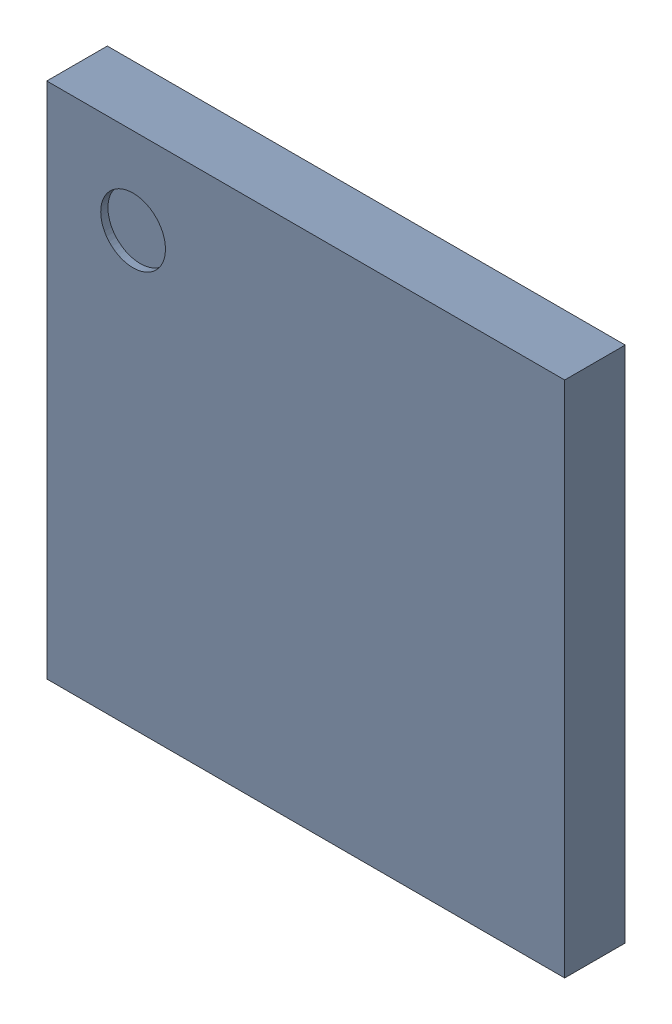
SolidWorks assembly 6297727008.step, configuration Default. Lengths in mm.
Overall size (7.1 9.92 0.85).
187 component instances, 3 part files, 0 mates.
Components (placement in the parent):
- Body (5).step-1: Body (5).step [Default] at (-3.55 -3.55 0.02) size (7.1 7.1 0.83)
  - Open CASCADE STEP translator 6.8 9.2.1.step-1: Open CASCADE STEP translator 6.8 9.2.1.step [Default] at origin size (7.1 7.1 0.83)
- Open CASCADE STEP translator 6.8 9.1.step-1: Open CASCADE STEP translator 6.8 9.1.step [Default] at (-3.55 -3.55 0.02) size (0.9 0.9 0.01)
- pinShape.step-1: pinShape.step [Default] at (-3 -3 0.02) size (0.25 0.25 0.02)
- pinShape.step-2: pinShape.step [Default] at (-2.75 -3 0.02) size (0.25 0.25 0.02)
- pinShape.step-3: pinShape.step [Default] at (-2.5 -3 0.02) size (0.25 0.25 0.02)
- pinShape.step-4: pinShape.step [Default] at (-2.25 -3 0.02) size (0.25 0.25 0.02)
- pinShape.step-5: pinShape.step [Default] at (-2 -3 0.02) size (0.25 0.25 0.02)
- pinShape.step-6: pinShape.step [Default] at (-1.75 -3 0.02) size (0.25 0.25 0.02)
- pinShape.step-7: pinShape.step [Default] at (-1.5 -3 0.02) size (0.25 0.25 0.02)
- pinShape.step-8: pinShape.step [Default] at (-1.25 -3 0.02) size (0.25 0.25 0.02)
- pinShape.step-9: pinShape.step [Default] at (-1 -3 0.02) size (0.25 0.25 0.02)
- pinShape.step-10: pinShape.step [Default] at (-0.75 -3 0.02) size (0.25 0.25 0.02)
- pinShape.step-11: pinShape.step [Default] at (-0.5 -3 0.02) size (0.25 0.25 0.02)
- pinShape.step-12: pinShape.step [Default] at (-0.25 -3 0.02) size (0.25 0.25 0.02)
- pinShape.step-13: pinShape.step [Default] at (0 -3 0.02) size (0.25 0.25 0.02)
- pinShape.step-14: pinShape.step [Default] at (0.25 -3 0.02) size (0.25 0.25 0.02)
- pinShape.step-15: pinShape.step [Default] at (0.5 -3 0.02) size (0.25 0.25 0.02)
- pinShape.step-16: pinShape.step [Default] at (0.75 -3 0.02) size (0.25 0.25 0.02)
- pinShape.step-17: pinShape.step [Default] at (1 -3 0.02) size (0.25 0.25 0.02)
- pinShape.step-18: pinShape.step [Default] at (1.25 -3 0.02) size (0.25 0.25 0.02)
- pinShape.step-19: pinShape.step [Default] at (1.5 -3 0.02) size (0.25 0.25 0.02)
- pinShape.step-20: pinShape.step [Default] at (1.75 -3 0.02) size (0.25 0.25 0.02)
- pinShape.step-21: pinShape.step [Default] at (2 -3 0.02) size (0.25 0.25 0.02)
- pinShape.step-22: pinShape.step [Default] at (2.25 -3 0.02) size (0.25 0.25 0.02)
- pinShape.step-23: pinShape.step [Default] at (2.5 -3 0.02) size (0.25 0.25 0.02)
- pinShape.step-24: pinShape.step [Default] at (2.75 -3 0.02) size (0.25 0.25 0.02)
- pinShape.step-25: pinShape.step [Default] at (3 -3 0.02) size (0.25 0.25 0.02)
- pinShape.step-26: pinShape.step [Default] at (-3 -2.75 0.02) size (0.25 0.25 0.02)
- pinShape.step-27: pinShape.step [Default] at (-2.75 -2.75 0.02) size (0.25 0.25 0.02)
- pinShape.step-28: pinShape.step [Default] at (-2.5 -2.75 0.02) size (0.25 0.25 0.02)
- pinShape.step-29: pinShape.step [Default] at (-2.25 -2.75 0.02) size (0.25 0.25 0.02)
- pinShape.step-30: pinShape.step [Default] at (-2 -2.75 0.02) size (0.25 0.25 0.02)
- pinShape.step-31: pinShape.step [Default] at (-1.75 -2.75 0.02) size (0.25 0.25 0.02)
- pinShape.step-32: pinShape.step [Default] at (-1.5 -2.75 0.02) size (0.25 0.25 0.02)
- pinShape.step-33: pinShape.step [Default] at (-1.25 -2.75 0.02) size (0.25 0.25 0.02)
- pinShape.step-34: pinShape.step [Default] at (-1 -2.75 0.02) size (0.25 0.25 0.02)
- pinShape.step-35: pinShape.step [Default] at (-0.75 -2.75 0.02) size (0.25 0.25 0.02)
- pinShape.step-36: pinShape.step [Default] at (-0.5 -2.75 0.02) size (0.25 0.25 0.02)
- pinShape.step-37: pinShape.step [Default] at (-0.25 -2.75 0.02) size (0.25 0.25 0.02)
- pinShape.step-38: pinShape.step [Default] at (0 -2.75 0.02) size (0.25 0.25 0.02)
- pinShape.step-39: pinShape.step [Default] at (0.25 -2.75 0.02) size (0.25 0.25 0.02)
- pinShape.step-40: pinShape.step [Default] at (0.5 -2.75 0.02) size (0.25 0.25 0.02)
- pinShape.step-41: pinShape.step [Default] at (0.75 -2.75 0.02) size (0.25 0.25 0.02)
- pinShape.step-42: pinShape.step [Default] at (1 -2.75 0.02) size (0.25 0.25 0.02)
- pinShape.step-43: pinShape.step [Default] at (1.25 -2.75 0.02) size (0.25 0.25 0.02)
- pinShape.step-44: pinShape.step [Default] at (1.5 -2.75 0.02) size (0.25 0.25 0.02)
- pinShape.step-45: pinShape.step [Default] at (1.75 -2.75 0.02) size (0.25 0.25 0.02)
- pinShape.step-46: pinShape.step [Default] at (2 -2.75 0.02) size (0.25 0.25 0.02)
- pinShape.step-47: pinShape.step [Default] at (2.25 -2.75 0.02) size (0.25 0.25 0.02)
- pinShape.step-48: pinShape.step [Default] at (2.5 -2.75 0.02) size (0.25 0.25 0.02)
- pinShape.step-49: pinShape.step [Default] at (2.75 -2.75 0.02) size (0.25 0.25 0.02)
- pinShape.step-50: pinShape.step [Default] at (3 -2.75 0.02) size (0.25 0.25 0.02)
- pinShape.step-51: pinShape.step [Default] at (-3 -2.5 0.02) size (0.25 0.25 0.02)
- pinShape.step-52: pinShape.step [Default] at (-2.75 -2.5 0.02) size (0.25 0.25 0.02)
- pinShape.step-53: pinShape.step [Default] at (2.75 -2.5 0.02) size (0.25 0.25 0.02)
- pinShape.step-54: pinShape.step [Default] at (3 -2.5 0.02) size (0.25 0.25 0.02)
- pinShape.step-55: pinShape.step [Default] at (-3 -2.25 0.02) size (0.25 0.25 0.02)
- pinShape.step-56: pinShape.step [Default] at (-2.75 -2.25 0.02) size (0.25 0.25 0.02)
- pinShape.step-57: pinShape.step [Default] at (2.75 -2.25 0.02) size (0.25 0.25 0.02)
- pinShape.step-58: pinShape.step [Default] at (3 -2.25 0.02) size (0.25 0.25 0.02)
- pinShape.step-59: pinShape.step [Default] at (-3 -2 0.02) size (0.25 0.25 0.02)
- pinShape.step-60: pinShape.step [Default] at (-2.75 -2 0.02) size (0.25 0.25 0.02)
- pinShape.step-61: pinShape.step [Default] at (2.75 -2 0.02) size (0.25 0.25 0.02)
- pinShape.step-62: pinShape.step [Default] at (3 -2 0.02) size (0.25 0.25 0.02)
- pinShape.step-63: pinShape.step [Default] at (-3 -1.75 0.02) size (0.25 0.25 0.02)
- pinShape.step-64: pinShape.step [Default] at (-2.75 -1.75 0.02) size (0.25 0.25 0.02)
- pinShape.step-65: pinShape.step [Default] at (2.75 -1.75 0.02) size (0.25 0.25 0.02)
- pinShape.step-66: pinShape.step [Default] at (3 -1.75 0.02) size (0.25 0.25 0.02)
- pinShape.step-67: pinShape.step [Default] at (-3 -1.5 0.02) size (0.25 0.25 0.02)
- pinShape.step-68: pinShape.step [Default] at (-2.75 -1.5 0.02) size (0.25 0.25 0.02)
- pinShape.step-69: pinShape.step [Default] at (2.75 -1.5 0.02) size (0.25 0.25 0.02)
- pinShape.step-70: pinShape.step [Default] at (3 -1.5 0.02) size (0.25 0.25 0.02)
- pinShape.step-71: pinShape.step [Default] at (-3 -1.25 0.02) size (0.25 0.25 0.02)
- pinShape.step-72: pinShape.step [Default] at (-2.75 -1.25 0.02) size (0.25 0.25 0.02)
- pinShape.step-73: pinShape.step [Default] at (2.75 -1.25 0.02) size (0.25 0.25 0.02)
- pinShape.step-74: pinShape.step [Default] at (3 -1.25 0.02) size (0.25 0.25 0.02)
- pinShape.step-75: pinShape.step [Default] at (-3 -1 0.02) size (0.25 0.25 0.02)
- pinShape.step-76: pinShape.step [Default] at (-2.75 -1 0.02) size (0.25 0.25 0.02)
- pinShape.step-77: pinShape.step [Default] at (2.75 -1 0.02) size (0.25 0.25 0.02)
- pinShape.step-78: pinShape.step [Default] at (3 -1 0.02) size (0.25 0.25 0.02)
- pinShape.step-79: pinShape.step [Default] at (-3 -0.75 0.02) size (0.25 0.25 0.02)
- pinShape.step-80: pinShape.step [Default] at (-2.75 -0.75 0.02) size (0.25 0.25 0.02)
- pinShape.step-81: pinShape.step [Default] at (2.75 -0.75 0.02) size (0.25 0.25 0.02)
- pinShape.step-82: pinShape.step [Default] at (3 -0.75 0.02) size (0.25 0.25 0.02)
- pinShape.step-83: pinShape.step [Default] at (-3 -0.5 0.02) size (0.25 0.25 0.02)
- pinShape.step-84: pinShape.step [Default] at (-2.75 -0.5 0.02) size (0.25 0.25 0.02)
- pinShape.step-85: pinShape.step [Default] at (2.75 -0.5 0.02) size (0.25 0.25 0.02)
- pinShape.step-86: pinShape.step [Default] at (3 -0.5 0.02) size (0.25 0.25 0.02)
- pinShape.step-87: pinShape.step [Default] at (-3 -0.25 0.02) size (0.25 0.25 0.02)
- pinShape.step-88: pinShape.step [Default] at (-2.75 -0.25 0.02) size (0.25 0.25 0.02)
- pinShape.step-89: pinShape.step [Default] at (2.75 -0.25 0.02) size (0.25 0.25 0.02)
- pinShape.step-90: pinShape.step [Default] at (3 -0.25 0.02) size (0.25 0.25 0.02)
- pinShape.step-91: pinShape.step [Default] at (-3 0 0.02) size (0.25 0.25 0.02)
- pinShape.step-92: pinShape.step [Default] at (-2.75 0 0.02) size (0.25 0.25 0.02)
- pinShape.step-93: pinShape.step [Default] at (2.75 0 0.02) size (0.25 0.25 0.02)
- pinShape.step-94: pinShape.step [Default] at (3 0 0.02) size (0.25 0.25 0.02)
- pinShape.step-95: pinShape.step [Default] at (-3 0.25 0.02) size (0.25 0.25 0.02)
- pinShape.step-96: pinShape.step [Default] at (-2.75 0.25 0.02) size (0.25 0.25 0.02)
- pinShape.step-97: pinShape.step [Default] at (2.75 0.25 0.02) size (0.25 0.25 0.02)
- pinShape.step-98: pinShape.step [Default] at (3 0.25 0.02) size (0.25 0.25 0.02)
- pinShape.step-99: pinShape.step [Default] at (-3 0.5 0.02) size (0.25 0.25 0.02)
- pinShape.step-100: pinShape.step [Default] at (-2.75 0.5 0.02) size (0.25 0.25 0.02)
- pinShape.step-101: pinShape.step [Default] at (2.75 0.5 0.02) size (0.25 0.25 0.02)
- pinShape.step-102: pinShape.step [Default] at (3 0.5 0.02) size (0.25 0.25 0.02)
- pinShape.step-103: pinShape.step [Default] at (-3 0.75 0.02) size (0.25 0.25 0.02)
- pinShape.step-104: pinShape.step [Default] at (-2.75 0.75 0.02) size (0.25 0.25 0.02)
- pinShape.step-105: pinShape.step [Default] at (2.75 0.75 0.02) size (0.25 0.25 0.02)
- pinShape.step-106: pinShape.step [Default] at (3 0.75 0.02) size (0.25 0.25 0.02)
- pinShape.step-107: pinShape.step [Default] at (-3 1 0.02) size (0.25 0.25 0.02)
- pinShape.step-108: pinShape.step [Default] at (-2.75 1 0.02) size (0.25 0.25 0.02)
- pinShape.step-109: pinShape.step [Default] at (2.75 1 0.02) size (0.25 0.25 0.02)
- pinShape.step-110: pinShape.step [Default] at (3 1 0.02) size (0.25 0.25 0.02)
- pinShape.step-111: pinShape.step [Default] at (-3 1.25 0.02) size (0.25 0.25 0.02)
- pinShape.step-112: pinShape.step [Default] at (-2.75 1.25 0.02) size (0.25 0.25 0.02)
- pinShape.step-113: pinShape.step [Default] at (2.75 1.25 0.02) size (0.25 0.25 0.02)
- pinShape.step-114: pinShape.step [Default] at (3 1.25 0.02) size (0.25 0.25 0.02)
- pinShape.step-115: pinShape.step [Default] at (-3 1.5 0.02) size (0.25 0.25 0.02)
- pinShape.step-116: pinShape.step [Default] at (-2.75 1.5 0.02) size (0.25 0.25 0.02)
- pinShape.step-117: pinShape.step [Default] at (2.75 1.5 0.02) size (0.25 0.25 0.02)
- pinShape.step-118: pinShape.step [Default] at (3 1.5 0.02) size (0.25 0.25 0.02)
- pinShape.step-119: pinShape.step [Default] at (-3 1.75 0.02) size (0.25 0.25 0.02)
- pinShape.step-120: pinShape.step [Default] at (-2.75 1.75 0.02) size (0.25 0.25 0.02)
- pinShape.step-121: pinShape.step [Default] at (2.75 1.75 0.02) size (0.25 0.25 0.02)
- pinShape.step-122: pinShape.step [Default] at (3 1.75 0.02) size (0.25 0.25 0.02)
- pinShape.step-123: pinShape.step [Default] at (-3 2 0.02) size (0.25 0.25 0.02)
- pinShape.step-124: pinShape.step [Default] at (-2.75 2 0.02) size (0.25 0.25 0.02)
- pinShape.step-125: pinShape.step [Default] at (2.75 2 0.02) size (0.25 0.25 0.02)
- pinShape.step-126: pinShape.step [Default] at (3 2 0.02) size (0.25 0.25 0.02)
- pinShape.step-127: pinShape.step [Default] at (-3 2.25 0.02) size (0.25 0.25 0.02)
- pinShape.step-128: pinShape.step [Default] at (-2.75 2.25 0.02) size (0.25 0.25 0.02)
- pinShape.step-129: pinShape.step [Default] at (2.75 2.25 0.02) size (0.25 0.25 0.02)
- pinShape.step-130: pinShape.step [Default] at (3 2.25 0.02) size (0.25 0.25 0.02)
- pinShape.step-131: pinShape.step [Default] at (-3 2.5 0.02) size (0.25 0.25 0.02)
- pinShape.step-132: pinShape.step [Default] at (-2.75 2.5 0.02) size (0.25 0.25 0.02)
- pinShape.step-133: pinShape.step [Default] at (2.75 2.5 0.02) size (0.25 0.25 0.02)
- pinShape.step-134: pinShape.step [Default] at (3 2.5 0.02) size (0.25 0.25 0.02)
- pinShape.step-135: pinShape.step [Default] at (-3 2.75 0.02) size (0.25 0.25 0.02)
- pinShape.step-136: pinShape.step [Default] at (-2.75 2.75 0.02) size (0.25 0.25 0.02)
- pinShape.step-137: pinShape.step [Default] at (-2.5 2.75 0.02) size (0.25 0.25 0.02)
- pinShape.step-138: pinShape.step [Default] at (-2.25 2.75 0.02) size (0.25 0.25 0.02)
- pinShape.step-139: pinShape.step [Default] at (-2 2.75 0.02) size (0.25 0.25 0.02)
- pinShape.step-140: pinShape.step [Default] at (-1.75 2.75 0.02) size (0.25 0.25 0.02)
- pinShape.step-141: pinShape.step [Default] at (-1.5 2.75 0.02) size (0.25 0.25 0.02)
- pinShape.step-142: pinShape.step [Default] at (-1.25 2.75 0.02) size (0.25 0.25 0.02)
- pinShape.step-143: pinShape.step [Default] at (-1 2.75 0.02) size (0.25 0.25 0.02)
- pinShape.step-144: pinShape.step [Default] at (-0.75 2.75 0.02) size (0.25 0.25 0.02)
- pinShape.step-145: pinShape.step [Default] at (-0.5 2.75 0.02) size (0.25 0.25 0.02)
- pinShape.step-146: pinShape.step [Default] at (-0.25 2.75 0.02) size (0.25 0.25 0.02)
- pinShape.step-147: pinShape.step [Default] at (0 2.75 0.02) size (0.25 0.25 0.02)
- pinShape.step-148: pinShape.step [Default] at (0.25 2.75 0.02) size (0.25 0.25 0.02)
- pinShape.step-149: pinShape.step [Default] at (0.5 2.75 0.02) size (0.25 0.25 0.02)
- pinShape.step-150: pinShape.step [Default] at (0.75 2.75 0.02) size (0.25 0.25 0.02)
- pinShape.step-151: pinShape.step [Default] at (1 2.75 0.02) size (0.25 0.25 0.02)
- pinShape.step-152: pinShape.step [Default] at (1.25 2.75 0.02) size (0.25 0.25 0.02)
- pinShape.step-153: pinShape.step [Default] at (1.5 2.75 0.02) size (0.25 0.25 0.02)
- pinShape.step-154: pinShape.step [Default] at (1.75 2.75 0.02) size (0.25 0.25 0.02)
- pinShape.step-155: pinShape.step [Default] at (2 2.75 0.02) size (0.25 0.25 0.02)
- pinShape.step-156: pinShape.step [Default] at (2.25 2.75 0.02) size (0.25 0.25 0.02)
- pinShape.step-157: pinShape.step [Default] at (2.5 2.75 0.02) size (0.25 0.25 0.02)
- pinShape.step-158: pinShape.step [Default] at (2.75 2.75 0.02) size (0.25 0.25 0.02)
- pinShape.step-159: pinShape.step [Default] at (3 2.75 0.02) size (0.25 0.25 0.02)
- pinShape.step-160: pinShape.step [Default] at (-3 3 0.02) size (0.25 0.25 0.02)
- pinShape.step-161: pinShape.step [Default] at (-2.75 3 0.02) size (0.25 0.25 0.02)
- pinShape.step-162: pinShape.step [Default] at (-2.5 3 0.02) size (0.25 0.25 0.02)
- pinShape.step-163: pinShape.step [Default] at (-2.25 3 0.02) size (0.25 0.25 0.02)
- pinShape.step-164: pinShape.step [Default] at (-2 3 0.02) size (0.25 0.25 0.02)
- pinShape.step-165: pinShape.step [Default] at (-1.75 3 0.02) size (0.25 0.25 0.02)
- pinShape.step-166: pinShape.step [Default] at (-1.5 3 0.02) size (0.25 0.25 0.02)
- pinShape.step-167: pinShape.step [Default] at (-1.25 3 0.02) size (0.25 0.25 0.02)
- pinShape.step-168: pinShape.step [Default] at (-1 3 0.02) size (0.25 0.25 0.02)
- pinShape.step-169: pinShape.step [Default] at (-0.75 3 0.02) size (0.25 0.25 0.02)
- pinShape.step-170: pinShape.step [Default] at (-0.5 3 0.02) size (0.25 0.25 0.02)
- pinShape.step-171: pinShape.step [Default] at (-0.25 3 0.02) size (0.25 0.25 0.02)
- pinShape.step-172: pinShape.step [Default] at (0 3 0.02) size (0.25 0.25 0.02)
- pinShape.step-173: pinShape.step [Default] at (0.25 3 0.02) size (0.25 0.25 0.02)
- pinShape.step-174: pinShape.step [Default] at (0.5 3 0.02) size (0.25 0.25 0.02)
- pinShape.step-175: pinShape.step [Default] at (0.75 3 0.02) size (0.25 0.25 0.02)
- pinShape.step-176: pinShape.step [Default] at (1 3 0.02) size (0.25 0.25 0.02)
- pinShape.step-177: pinShape.step [Default] at (1.25 3 0.02) size (0.25 0.25 0.02)
- pinShape.step-178: pinShape.step [Default] at (1.5 3 0.02) size (0.25 0.25 0.02)
- pinShape.step-179: pinShape.step [Default] at (1.75 3 0.02) size (0.25 0.25 0.02)
- pinShape.step-180: pinShape.step [Default] at (2 3 0.02) size (0.25 0.25 0.02)
- pinShape.step-181: pinShape.step [Default] at (2.25 3 0.02) size (0.25 0.25 0.02)
- pinShape.step-182: pinShape.step [Default] at (2.5 3 0.02) size (0.25 0.25 0.02)
- pinShape.step-183: pinShape.step [Default] at (2.75 3 0.02) size (0.25 0.25 0.02)
- pinShape.step-184: pinShape.step [Default] at (3 3 0.02) size (0.25 0.25 0.02)
